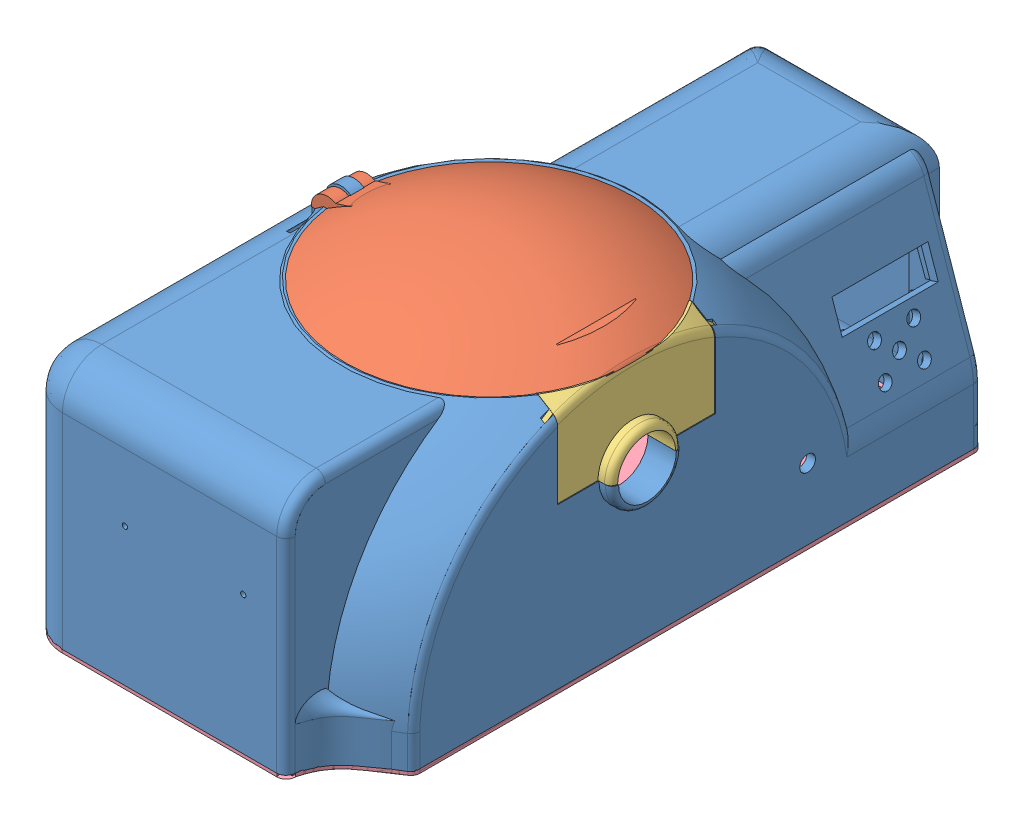
SolidWorks assembly capa 5 , configuration Valor predeterminado. Lengths in mm.
Overall size (267.31 225.19 495.2).
4 component instances, 4 part files, 0 mates.
Components (placement in the parent):
- capa sem tampa 17 06-1: capa sem tampa 17 06 [Valor predeterminado] at (-78.2896 27.0845 1074.357) size (263.5 196.39 495)
- tampa capa 2 16 06-1: tampa capa 2 16 06 [Valor predeterminado] at (-77.7761 25.766 1075.3208) size (258.3 217.2 455.39)
- tampa frente 17 06-1: tampa frente 17 06 [Valor predeterminado] at (-78.8131 27.234 1074.4769) size (255 183.2 455.39)
- tampa nova1-1: tampa nova1 [Valor predeterminado] at (-78.2578 23.5787 1074.2075) size (245.29 10.99 495.15)
